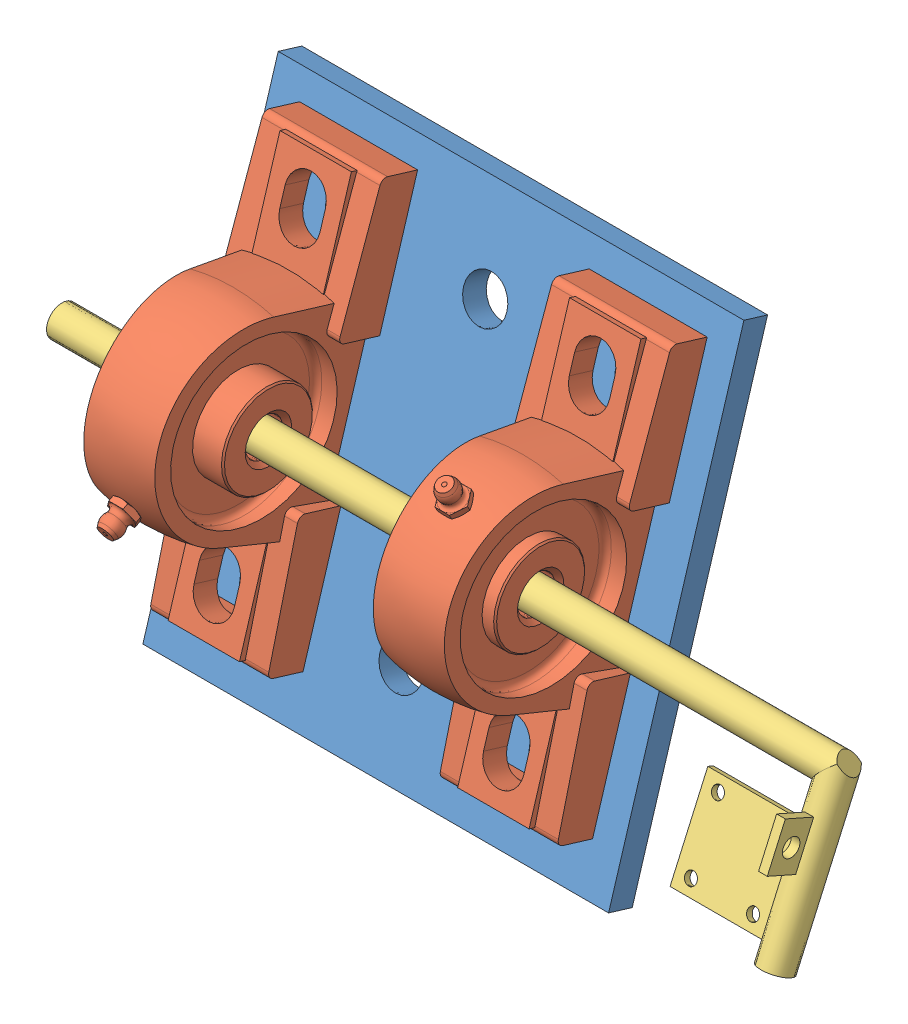
SolidWorks assembly Assem1, configuration Default. Lengths in mm.
Overall size (255 155.5 105.59).
4 component instances, 3 part files, 11 mates.
Components (placement in the parent):
- Base_plate-1: Base_plate [Default] x (1 0 0) z (0 -0.956835 0.290633) size (150 7.96 150)
- ucp201-1: ucp201 [Default] at (28.3715 83.4102 6.2271) x (0 0.956835 -0.290633) z (1 0 0) size (127 61.24 38)
- ucp201-4: ucp201 [Default] at (121.6285 83.4102 6.2271) x (0 -0.956835 0.290633) z (-1 0 0) size (127 61.24 38)
- Rods-1: Rods [Default] at (80.1917 83.4102 6.2271) x (1 0 0) z (0 -0.914112 0.405461) size (255 20 55)
Mates (geometry in assembly coordinates):
- Coincident2: coincident: point of Base_plate-1
- Coincident3: coincident: plane of Base_plate-1 through (150 0 0) normal (0 0.290633 0.956835)
- Coincident4: coincident aligned: plane of Base_plate-1 through (0 0 0) normal (1 0 0)
- Concentric1: concentric anti-aligned: circle of Base_plate-1; circle of ucp201-1
- Concentric2: concentric anti-aligned: circle of Base_plate-1; circle of ucp201-1
- Coincident9: coincident anti-aligned: plane of Base_plate-1 through (150 0 0) normal (0 0.290633 0.956835); plane of ucp201-1 through (-28.6285 95.2051 -28.918) normal (0 -0.290633 -0.956835)
- Coincident13: coincident anti-aligned: plane of Base_plate-1 through (150 0 0) normal (0 0.290633 0.956835); plane of ucp201-4 through (178.6285 135.3921 -41.1245) normal (0 -0.290633 -0.956835)
- Concentric9: concentric: circle of ucp201-1; circle of Rods-1
- Concentric10: concentric aligned: circle of Base_plate-1; circle of ucp201-4
- Concentric11: concentric aligned: circle of Base_plate-1; circle of ucp201-4
- Concentric12: concentric anti-aligned: circle of ucp201-1; circle of Rods-1
